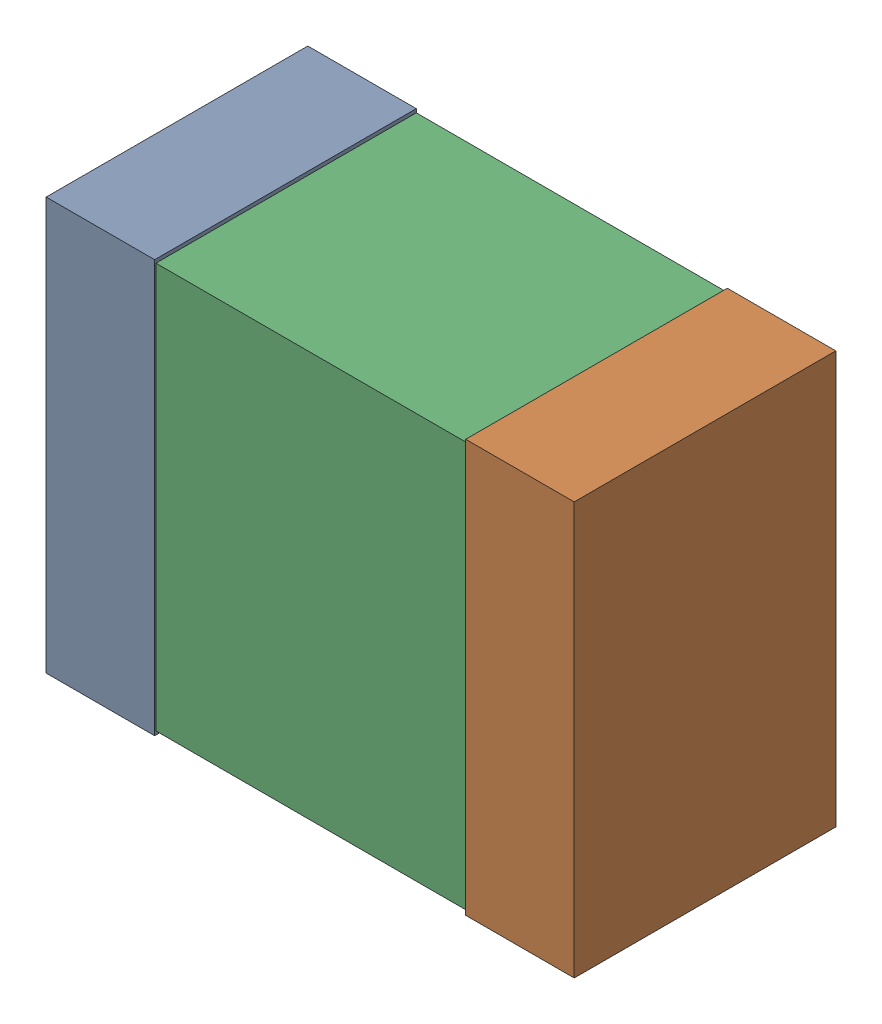
SolidWorks assembly CinB3_1Kanaloa_v2.0.0_Power, configuration Default. Lengths in mm.
Overall size (3.65 2.85 1.81).
6 component instances, 2 part files, 0 mates.
Components (placement in the parent):
- 334788400-1: 334788400 [Default] at (126.8 54.375 0) size (0.75 2.85 1.81)
  - Extruded_5-1: Extruded_5 [Default] at origin size (0.75 2.85 1.81)
- 334788400-2: 334788400 [Default] at (129.7 54.375 0) size (0.75 2.85 1.81)
  - Extruded_5-1: Extruded_5 [Default] at origin size (0.75 2.85 1.81)
- 334788784-1: 334788784 [Default] at (128.25 54.375 0) size (3.6 2.8 1.8)
  - Extruded_6-1: Extruded_6 [Default] at origin size (3.6 2.8 1.8)
